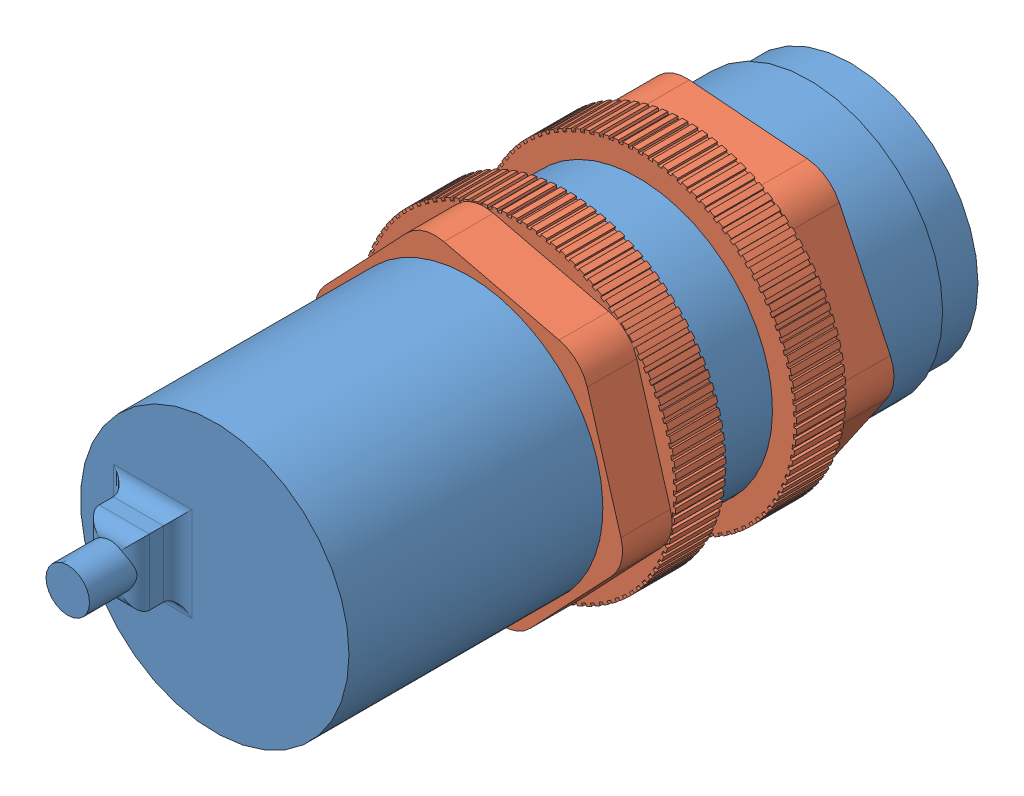
SolidWorks assembly mz80-cad, configuration Predeterminado. Lengths in mm.
Overall size (31.67 31.67 51).
3 component instances, 2 part files, 0 mates.
Components (placement in the parent):
- MZ80-1: MZ80 [Predeterminado] at origin size (19 19 51)
- MZ80-Kapak-1: MZ80-Kapak [Predeterminado] at (0 0 27.0394) x (-0.689084 -0.724681 0) z (0 0 -1) size (22.4 22.4 7)
- MZ80-Kapak-2: MZ80-Kapak [Predeterminado] at (0 0 8.0394) x (0.997024 -0.077086 0) z (0 0 1) size (22.4 22.4 7)
